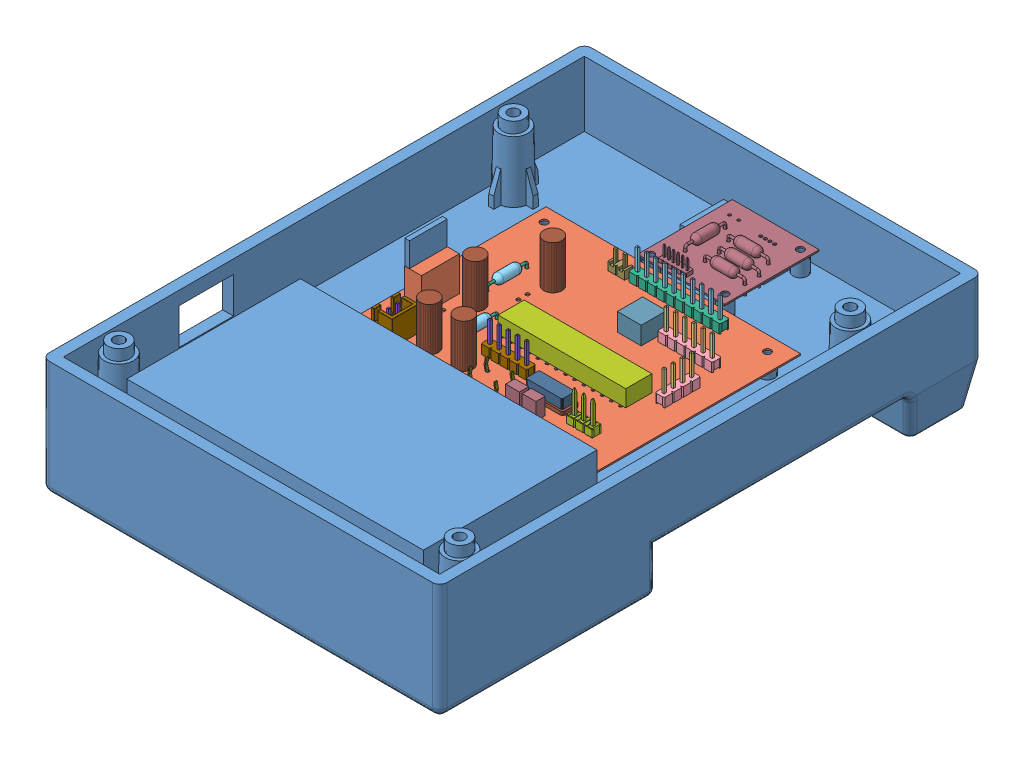
SolidWorks assembly Lower Half Of The Enclosure, configuration Default. Lengths in mm.
Overall size (110.21 39.11 150).
110 component instances, 32 part files, 2 mates.
Components (placement in the parent):
- RGBLOWER-1: RGBLOWER [Default] at (105.6668 49.108 59.4545) x (0 0 1) z (-1 0 0) size (150 33.75 110.21)
- PCB1_new.step-1: PCB1_new.step [Default] at (113.4548 56.5195 207.1385) x (0 0 -1) z (0 1 0) size (60.07 70.36 37.41)
  - Board.step-1: Board.step [Default] at origin size (60.07 70.36 0.41)
    - Open CASCADE STEP translator 6.8 1.1.1.step-1: Open CASCADE STEP translator 6.8 1.1.1.step [Default] at (0 0 -0.4115) size (60.07 70.36 0.41)
  - USBASAP.step-1: USBASAP.step [Default] at origin size (2.54 15.24 11.54)
    - 61300611121.step-1: 61300611121.step [Default] at (100.3299 41.4021 1.3) x (0 1 0) z (1 0 0) size (15.24 11.54 2.54)
      - 6130xx11121_PIN.step-1: 6130xx11121_PIN.step [Default] at (-6.35 1.5 0) x (1 0 0) z (0 -1 0) size (0.64 0.64 11.54)
      - 6130xx11121_PIN.step-2: 6130xx11121_PIN.step [Default] at (-3.81 1.5 0) x (1 0 0) z (0 -1 0) size (0.64 0.64 11.54)
      - 6130xx11121_PIN.step-3: 6130xx11121_PIN.step [Default] at (-1.27 1.5 0) x (1 0 0) z (0 -1 0) size (0.64 0.64 11.54)
      - 6130xx11121_PIN.step-4: 6130xx11121_PIN.step [Default] at (1.27 1.5 0) x (1 0 0) z (0 -1 0) size (0.64 0.64 11.54)
      - 6130xx11121_PIN.step-5: 6130xx11121_PIN.step [Default] at (3.81 1.5 0) x (1 0 0) z (0 -1 0) size (0.64 0.64 11.54)
      - 6130xx11121_PIN.step-6: 6130xx11121_PIN.step [Default] at (6.35 1.5 0) x (1 0 0) z (0 -1 0) size (0.64 0.64 11.54)
      - 61300611121-0.step-1: 61300611121-0.step [Default] at origin size (15.24 2.54 2.54)
  - R2.step-1: R2.step [Default] at origin size (11.64 2.69 5.34)
    - Res_Vishay_RNC55H1002FSB14_eec.step-1: Res_Vishay_RNC55H1002FSB14_eec.step [Default] at (76.962 76.708 0) x (1 0 0) z (0 0 1) size (11.64 2.69 5.34)
      - Body.step-1: Body.step [Default] at (3.555 0 1.35) x (0 -1 0) z (-1 0 0) size (2.69 2.69 7.11)
      - Leads.step-1: Leads.step [Default] at (0 0 1.35) x (0 -1 0) z (-1 0 0) size (0.64 4.32 11.64)
  - U_.step-1: U_.step [Default] at origin size (7.2 35.3 4.58)
    - 6221692192.step-1: 6221692192.step [Default] at (82.423 55.118 0) size (7.2 35.3 4.58)
      - Extruded.step-1: Extruded.step [Default] at origin size (7.2 35.3 4.58)
  - KEYC.step-1: KEYC.step [Default] at origin size (2.54 12.7 11.54)
    - 61300511121.step-1: 61300511121.step [Default] at (72.8981 64.0079 1.3) x (0 -1 0) z (-1 0 0) size (12.7 11.54 2.54)
      - 6130xx11121_PIN-1.step-1: 6130xx11121_PIN-1.step [Default] at (-5.08 1.5 0) x (1 0 0) z (0 -1 0) size (0.64 0.64 11.54)
      - 6130xx11121_PIN-1.step-2: 6130xx11121_PIN-1.step [Default] at (-2.54 1.5 0) x (1 0 0) z (0 -1 0) size (0.64 0.64 11.54)
      - 6130xx11121_PIN-1.step-3: 6130xx11121_PIN-1.step [Default] at (0 1.5 0) x (1 0 0) z (0 -1 0) size (0.64 0.64 11.54)
      - 6130xx11121_PIN-1.step-4: 6130xx11121_PIN-1.step [Default] at (2.54 1.5 0) x (1 0 0) z (0 -1 0) size (0.64 0.64 11.54)
      - 6130xx11121_PIN-1.step-5: 6130xx11121_PIN-1.step [Default] at (5.08 1.5 0) x (1 0 0) z (0 -1 0) size (0.64 0.64 11.54)
      - 61300511121-2.step-1: 61300511121-2.step [Default] at origin size (12.7 2.54 2.54)
  - xtal1.step-1: xtal1.step [Default] at origin size (4.65 11.36 3.61)
    - 6221692752.step-1: 6221692752.step [Default] at (70.3579 49.7839 1) size (3.7 10.05 2.6)
      - Extruded-3.step-1: Extruded-3.step [Default] at origin size (3.7 10.05 2.6)
    - 6221692672.step-1: 6221692672.step [Default] at (70.3581 49.7839 0) size (4.65 11.36 1.01)
      - Extruded-4.step-1: Extruded-4.step [Default] at origin size (4.65 11.36 1.01)
  - C2.step-1: C2.step [Default] at origin size (2.54 3.81 11.66)
    - 6221692592.step-1: 6221692592.step [Default] at (64.516 49.9111 -7) size (0.51 0.51 7)
      - Extruded-5.step-1: Extruded-5.step [Default] at origin size (0.51 0.51 7)
    - 6221692592.step-2: 6221692592.step [Default] at (64.5159 47.3711 -7) size (0.51 0.51 7)
      - Extruded-5.step-1: Extruded-5.step [Default] at origin size (0.51 0.51 7)
    - 6221691872.step-1: 6221691872.step [Default] at (64.516 48.641 0) size (2.54 3.81 4.66)
      - Extruded-6.step-1: Extruded-6.step [Default] at origin size (2.54 3.81 4.66)
  - C1.step-1: C1.step [Default] at origin size (2.54 3.81 11.66)
    - 6221692592.step-1: 6221692592.step [Default] at (64.5159 51.9431 -7) size (0.51 0.51 7)
      - Extruded-5.step-1: Extruded-5.step [Default] at origin size (0.51 0.51 7)
    - 6221692592.step-2: 6221692592.step [Default] at (64.516 54.4831 -7) size (0.51 0.51 7)
      - Extruded-5.step-1: Extruded-5.step [Default] at origin size (0.51 0.51 7)
    - 6221691872.step-1: 6221691872.step [Default] at (64.516 53.213 0) size (2.54 3.81 4.66)
      - Extruded-6.step-1: Extruded-6.step [Default] at origin size (2.54 3.81 4.66)
  - VR1.step-1: VR1.step [Default] at origin size (6.99 6.6 4.95)
    - 6221690432.step-1: 6221690432.step [Default] at (99.279 53.467 0) size (6.99 6.6 4.95)
      - Extruded-7.step-1: Extruded-7.step [Default] at origin size (6.99 6.6 4.95)
  - SW1.step-1: SW1.step [Default] at origin size (5.99 7.8 20.81)
    - Switch_TE_Connectivity_3-1825910-1_eec.step-1: Switch_TE_Connectivity_3-1825910-1_eec.step [Default] at (66.33 62.178 -0.4115) x (-1 0 0) z (0 0 -1) size (5.99 7.8 20.81)
      - 1.step-1: 1.step [Default] at (0 0 17) size (5.79 5.79 0.1)
      - 2.step-1: 2.step [Default] at (0 0 17) size (5.21 7.8 4.81)
      - c-3-1825910-1-c-3d.step-1: c-3-1825910-1-c-3d.step [Default] at (0 0 17) size (5.99 5.99 17.3)
      - TE_connectivity_Logo_1_(2).step-1: TE_connectivity_Logo_1_(2).step [Default] at (2.896 6.1453 2.0379) x (0 -1 0) z (1 0 0) size (1.87 0.66 0.1)
  - Reg.step-1: Reg.step [Default] at origin size (10.5 4.7 16.2)
    - 6221691472.step-1: 6221691472.step [Default] at (74.422 88.306 13.05) size (10.4 1.3 6.65)
      - Extruded-8.step-1: Extruded-8.step [Default] at origin size (10.4 1.3 6.65)
    - 6221691312.step-1: 6221691312.step [Default] at (74.422 86.656 3.5) size (10.5 4.7 9.55)
      - Extruded-9.step-1: Extruded-9.step [Default] at origin size (10.5 4.7 9.55)
  - R1.step-1: R1.step [Default] at origin size (11.64 2.69 5.34)
    - Res_Vishay_RNC55H1002FSB14_eec.step-1: Res_Vishay_RNC55H1002FSB14_eec.step [Default] at (93.218 84.709 0) x (1 0 0) z (0 0 1) size (11.64 2.69 5.34)
      - Body.step-1: Body.step [Default] at (3.555 0 1.35) x (0 -1 0) z (-1 0 0) size (2.69 2.69 7.11)
      - Leads.step-1: Leads.step [Default] at (0 0 1.35) x (0 -1 0) z (-1 0 0) size (0.64 4.32 11.64)
  - P1.step-1: P1.step [Default] at origin size (10.16 2.54 11.54)
    - 61300411121.step-1: 61300411121.step [Default] at (89.0271 33.2741 1.3) x (1 0 0) z (0 -1 0) size (10.16 11.54 2.54)
      - 6130xx11121_PIN-10.step-1: 6130xx11121_PIN-10.step [Default] at (-3.81 1.5 0) x (1 0 0) z (0 -1 0) size (0.64 0.64 11.54)
      - 6130xx11121_PIN-10.step-2: 6130xx11121_PIN-10.step [Default] at (-1.27 1.5 0) x (1 0 0) z (0 -1 0) size (0.64 0.64 11.54)
      - 6130xx11121_PIN-10.step-3: 6130xx11121_PIN-10.step [Default] at (1.27 1.5 0) x (1 0 0) z (0 -1 0) size (0.64 0.64 11.54)
      - 6130xx11121_PIN-10.step-4: 6130xx11121_PIN-10.step [Default] at (3.81 1.5 0) x (1 0 0) z (0 -1 0) size (0.64 0.64 11.54)
      - 61300411121-11.step-1: 61300411121-11.step [Default] at origin size (10.16 2.54 2.54)
  - LCD.step-1: LCD.step [Default] at origin size (2.54 25.4 11.54)
    - 61301011121.step-1: 61301011121.step [Default] at (110.6169 54.6101 1.3) x (0 1 0) z (1 0 0) size (25.4 11.54 2.54)
      - 6130xx11121_PIN-12.step-1: 6130xx11121_PIN-12.step [Default] at (-11.43 1.5 0) x (1 0 0) z (0 -1 0) size (0.64 0.64 11.54)
      - 6130xx11121_PIN-12.step-2: 6130xx11121_PIN-12.step [Default] at (-8.89 1.5 0) x (1 0 0) z (0 -1 0) size (0.64 0.64 11.54)
      - 6130xx11121_PIN-12.step-3: 6130xx11121_PIN-12.step [Default] at (-6.35 1.5 0) x (1 0 0) z (0 -1 0) size (0.64 0.64 11.54)
      - 6130xx11121_PIN-12.step-4: 6130xx11121_PIN-12.step [Default] at (-3.81 1.5 0) x (1 0 0) z (0 -1 0) size (0.64 0.64 11.54)
      - 6130xx11121_PIN-12.step-5: 6130xx11121_PIN-12.step [Default] at (-1.27 1.5 0) x (1 0 0) z (0 -1 0) size (0.64 0.64 11.54)
      - 6130xx11121_PIN-12.step-6: 6130xx11121_PIN-12.step [Default] at (1.27 1.5 0) x (1 0 0) z (0 -1 0) size (0.64 0.64 11.54)
      - 6130xx11121_PIN-12.step-7: 6130xx11121_PIN-12.step [Default] at (3.81 1.5 0) x (1 0 0) z (0 -1 0) size (0.64 0.64 11.54)
      - 6130xx11121_PIN-12.step-8: 6130xx11121_PIN-12.step [Default] at (6.35 1.5 0) x (1 0 0) z (0 -1 0) size (0.64 0.64 11.54)
      - 6130xx11121_PIN-12.step-9: 6130xx11121_PIN-12.step [Default] at (8.89 1.5 0) x (1 0 0) z (0 -1 0) size (0.64 0.64 11.54)
      - 6130xx11121_PIN-12.step-10: 6130xx11121_PIN-12.step [Default] at (11.43 1.5 0) x (1 0 0) z (0 -1 0) size (0.64 0.64 11.54)
      - 61301011121-13.step-1: 61301011121-13.step [Default] at origin size (25.4 2.54 2.54)
  - KEYR.step-1: KEYR.step [Default] at origin size (2.49 7.62 11.56)
    - 022284033.step-1: 022284033.step [Default] at (68.0721 38.3539 1.138) x (0 1 0) z (1 0 0) size (7.62 11.56 2.49)
      - Open CASCADE STEP translator 6.8 1.15.1.1.step-1: Open CASCADE STEP translator 6.8 1.15.1.1.step [Default] at origin size (7.62 11.56 2.49)
      - Open CASCADE STEP translator 6.8 1.15.1.2.step-1: Open CASCADE STEP translator 6.8 1.15.1.2.step [Default] at origin
  - J1.step-1: J1.step [Default] at origin size (7.4 5.75 10.4)
    - Conn_JST_B2B-XH-A_LF_SN_eec.step-1: Conn_JST_B2B-XH-A_LF_SN_eec.step [Default] at (64.409 86.851 0) size (7.4 5.75 10.4)
      - 1-14.step-1: 1-14.step [Default] at (0 0.025 0) x (-1 0 0) z (0 1 0) size (7.4 10.4 5.75)
        - 1-15.step-1: 1-15.step [Default] at origin size (3.14 10.2 0.64)
        - B2B-XH-A.step-1: B2B-XH-A.step [Default] at origin size (7.4 7 5.75)
        - JST_Logo_adjustable.step-1: JST_Logo_adjustable.step [Default] at (-1.7267 5.5034 2.841) size (0.85 2.3 0.01)
  - C6.step-1: C6.step [Default] at origin size (5 5 12)
    - 6221692832.step-1: 6221692832.step [Default] at (66.929 70.358 0) size (5 5 12)
      - Extruded-16.step-1: Extruded-16.step [Default] at origin size (5 5 12)
  - C5.step-1: C5.step [Default] at origin size (5 5 12)
    - 6221692832.step-1: 6221692832.step [Default] at (82.804 83.058 0) size (5 5 12)
      - Extruded-16.step-1: Extruded-16.step [Default] at origin size (5 5 12)
  - C4.step-1: C4.step [Default] at origin size (5 5 12)
    - 6221692832.step-1: 6221692832.step [Default] at (66.167 79.121 0) size (5 5 12)
      - Extruded-16.step-1: Extruded-16.step [Default] at origin size (5 5 12)
  - C3.step-1: C3.step [Default] at origin size (5 5 12)
    - 6221692832.step-1: 6221692832.step [Default] at (98.044 76.851 0) size (5 5 12)
      - Extruded-16.step-1: Extruded-16.step [Default] at origin size (5 5 12)
  - ADCR.step-1: ADCR.step [Default] at origin size (2.34 4.67 11.18)
    - c-5-146280-2-d-3d.step-1: c-5-146280-2-d-3d.step [Default] at (110.3631 70.485 0) x (0 1 0) z (0 0 -1) size (4.67 2.34 11.18)
- Sensor_part_new (1).step-1: Sensor_part_new (1).step [Default] at (15.4341 56.5195 115.2732) x (1 0 0) z (0 1 0) size (24 26.16 6.7)
Mates (geometry in assembly coordinates):
- Coincident1: coincident anti-aligned: circle of RGBLOWER-1; circle of PCB1_new.step-1/Board.step-1/Open CASCADE STEP translator 6.8 1.1.1.step-1
- Coincident2: coincident anti-aligned: circle of RGBLOWER-1; circle of Sensor_part_new (1).step-1
